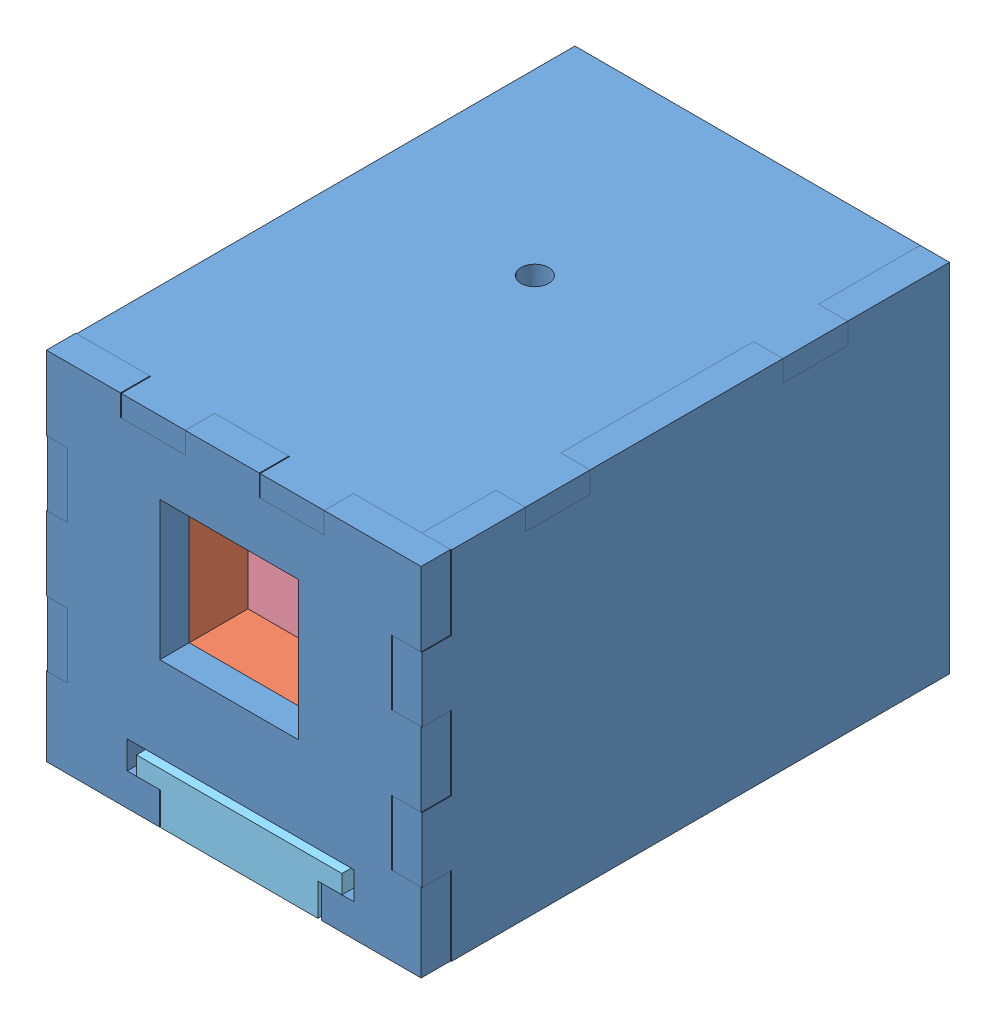
SolidWorks assembly nosepoke_assembly, configuration Default. Lengths in mm.
Overall size (40.57 38.5 57).
11 component instances, 5 part files, 18 mates.
Components (placement in the parent):
- nosepoke-1: nosepoke [Main Part] at (19.5614 28.6924 45.3731) size (40.47 38.5 57)
- nosepoke-2: nosepoke [Front Lid] at (19.4672 28.6924 45.3681) size (40.48 38.5 3.17)
- nosepoke_guard-1: nosepoke_guard [Default] at (49.9995 43.086 92.8481) size (21 18 6.35)
- preferenceV2_dispenser_IRAssembly - Copy-1: preferenceV2_dispenser_IRAssembly - Copy [Default] at (23.5614 61.6614 83.7481) x (1 0 0) z (0 -1 0) size (32.5 15.2 5)
  - sparkfunIR_LEDandCase-1: sparkfunIR_LEDandCase [2Pin] at (-11.0025 21.2786 44.4241) x (-1 0 0) z (0 0 -1) size (4.3 15.2 5)
    - sparkfunIR_casing-1: sparkfunIR_casing [Default] at (-40.6525 -5.8286 32.4491) x (1 0 0) z (0 0 -1) size (4.3 15.2 5)
  - sparkfunIR_LEDandCase-2: sparkfunIR_LEDandCase [3Pin] at (42.1025 21.2786 -20.4741) size (4.3 15.2 5)
    - sparkfunIR_casing-1: sparkfunIR_casing [Default] at (-40.6525 -5.8286 32.4491) x (1 0 0) z (0 0 -1) size (4.3 15.2 5)
- nosepoke_guard_backing-1: nosepoke_guard_backing [Default] at (28.7172 43.5464 89.6731) size (21 18 3.17)
- nosepoke-3: nosepoke [Side Section ] at (19.5614 28.6924 45.3731) size (3.17 38.5 57)
- nosepoke_magnet_mount-1: nosepoke_magnet_mount [Default] at (29.1914 31.1672 102.3731) size (22.2 5.5 55)
Mates (geometry in assembly coordinates):
- Coincident19: coincident anti-aligned: plane of nosepoke-1 through (22.8614 53.1864 76.1878) normal (1 0 0); plane of preferenceV2_dispenser_IRAssembly - Copy-1/sparkfunIR_LEDandCase-2/sparkfunIR_casing-1 through (22.8614 52.1864 99.1981) normal (-1 0 0)
- Coincident20: coincident aligned: plane of nosepoke-1 through (21.8614 30.8864 99.1981) normal (0 0 1); plane of preferenceV2_dispenser_IRAssembly - Copy-1/sparkfunIR_LEDandCase-2/sparkfunIR_casing-1 through (22.8614 52.1864 99.1981) normal (0 0 1)
- Coincident21: coincident anti-aligned: plane of nosepoke-1 through (27.8614 47.1864 76.1878) normal (0 1 0); plane of preferenceV2_dispenser_IRAssembly - Copy-1/sparkfunIR_LEDandCase-2/sparkfunIR_casing-1 through (25.0114 47.1864 99.1981) normal (0 -1 0)
- Coincident23: coincident anti-aligned: plane of nosepoke-1 through (55.3614 53.1864 76.1878) normal (-1 0 0); plane of preferenceV2_dispenser_IRAssembly - Copy-1/sparkfunIR_LEDandCase-1/sparkfunIR_casing-1 through (55.3614 47.1864 99.1981) normal (1 0 0)
- Coincident24: coincident anti-aligned: plane of nosepoke-1 through (19.5614 39.3864 102.3731) normal (0 -1 0); plane of nosepoke-2 through (19.4672 39.3864 91.5117) normal (0 1 0)
- Coincident25: coincident aligned: plane of nosepoke-1 through (19.5614 28.6924 102.3731) normal (0 0 1); plane of nosepoke-2 through (19.4672 28.6924 102.3731) normal (0 0 1)
- Coincident26: coincident aligned: plane of nosepoke-1 through (21.8614 69.3864 99.1981) normal (0 1 0); plane of nosepoke-2 through (19.4672 69.3864 102.3731) normal (0 1 0)
- Coincident27: coincident aligned: plane of nosepoke-2 through (31.7172 46.5464 99.1981) normal (1 0 0); plane of nosepoke_guard-1 through (31.7172 61.5464 99.1981) normal (1 0 0)
- Coincident28: coincident aligned: plane of nosepoke-2 through (39.2172 46.5464 99.1981) normal (0 1 0); plane of nosepoke_guard-1 through (31.7172 46.5464 99.1981) normal (0 1 0)
- Coincident29: coincident anti-aligned: plane of nosepoke_guard-1 through (49.9995 43.086 92.8481) normal (0 0 -1); plane of nosepoke_guard_backing-1 through (28.7172 43.5464 92.8481) normal (0 0 1)
- Coincident30: coincident aligned: plane of nosepoke_guard-1 through (49.7172 61.5464 99.1981) normal (1 0 0); plane of nosepoke_guard_backing-1 through (49.7172 43.5464 92.8481) normal (1 0 0)
- Coincident31: coincident aligned: plane of nosepoke_guard-1 through (46.7172 61.5464 99.1981) normal (0 1 0); plane of nosepoke_guard_backing-1 through (28.7172 61.5464 92.8481) normal (0 1 0)
- Coincident34: coincident anti-aligned: plane of nosepoke-1 through (60.0364 69.3864 63.3731) normal (0 0 1); plane of nosepoke-3 through (49.4932 69.3864 63.3731) normal (0 0 -1)
- Coincident35: coincident aligned: plane of nosepoke-1 through (21.8614 69.3864 99.1981) normal (0 1 0); plane of nosepoke-3 through (60.0364 69.3864 99.1981) normal (0 1 0)
- Coincident36: coincident aligned: plane of nosepoke-1 through (60.0364 28.6924 45.3731) normal (1 0 0); plane of nosepoke-3 through (60.0364 28.6924 45.3731) normal (1 0 0)
- Coincident42: coincident anti-aligned: plane of nosepoke-1 through (31.7914 34.3864 47.3731) normal (0 1 0); plane of nosepoke_magnet_mount-1 through (31.7914 34.3864 47.3731) normal (0 -1 0)
- Coincident43: coincident anti-aligned: plane of nosepoke-1 through (31.7914 30.8864 47.3731) normal (1 0 0); plane of nosepoke_magnet_mount-1 through (31.7914 30.8864 47.3731) normal (-1 0 0)
- Coincident44: coincident aligned: plane of nosepoke-2 through (19.4672 28.6924 102.3731) normal (0 0 1); plane of nosepoke_magnet_mount-1 through (29.1914 31.1672 102.3731) normal (0 0 1)
